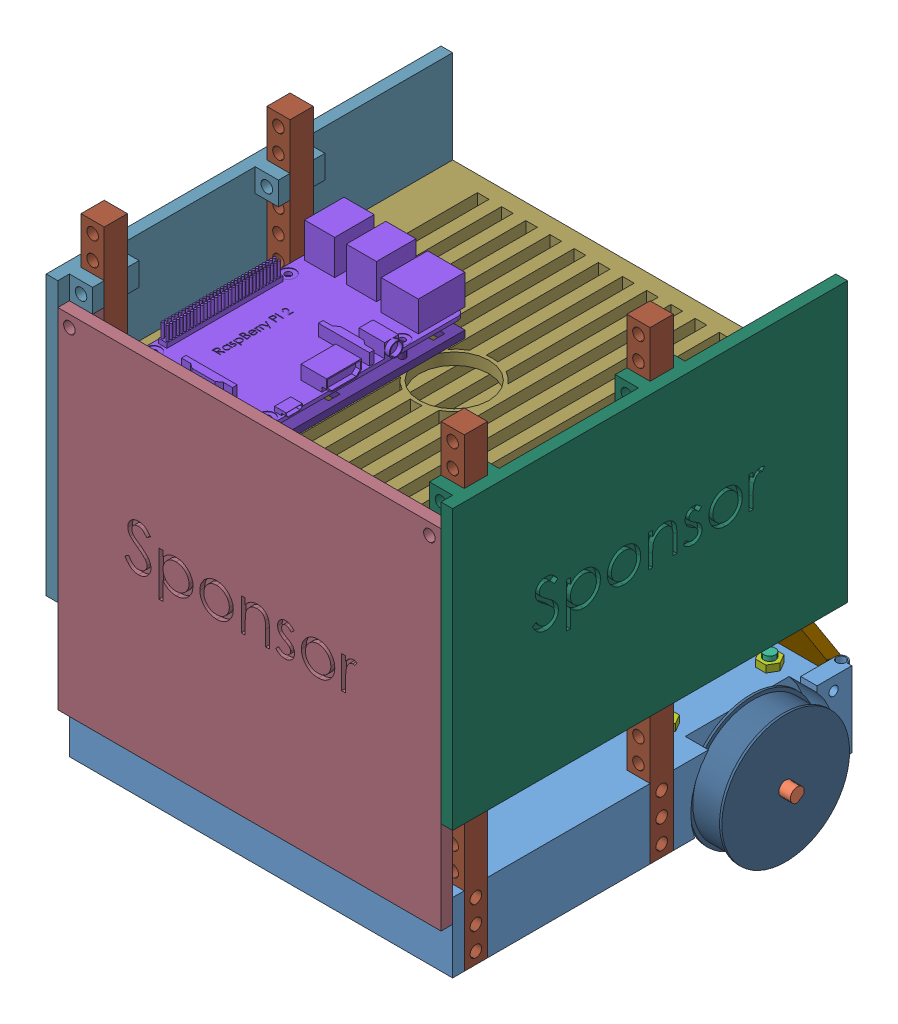
SolidWorks assembly base_robot2_assV4, configuration Défaut. Lengths in mm.
Overall size (196.8 228.59 210.36).
45 component instances, 19 part files, 95 mates.
Components (placement in the parent):
- base_robot2_modelV3-1: base_robot2_modelV3 [Défaut] at (-7.2062 -14.7881 165) size (169 32.5 172.25)
- moteur_IG320100-1: moteur_IG320100 [Défaut] at (-74.68 -4.7881 115) x (0 0.840643 0.541589) z (-1 0 0) size (32 32 94.7)
- moteur_IG320100-2: moteur_IG320100 [Défaut] at (60.2677 -4.7881 115) x (0 -0.613287 0.789861) z (1 0 0) size (32 32 94.7)
- patin_robot2_model-1: patin_robot2_model [Défaut] at (-59.7062 -24.7881 217.5) size (40 10 30)
- patin_robot2_model-2: patin_robot2_model [Défaut] at (45.2938 -24.7881 217.5) size (40 10 30)
- support_moteur_30mm-1: support_moteur_30mm [Défaut] at (11.7938 -4.7881 115) x (1 0 0) z (0 0 -1) size (10 9 52.36)
- support_moteur_30mm-2: support_moteur_30mm [Défaut] at (-26.2062 -4.7881 115) x (-1 0 0) z (0 0 1) size (10 9 52.36)
- support_moteur_32.02mm-1: support_moteur_32.02mm [Défaut] at (61.7938 -4.7881 115) x (-1 0 0) z (0 0 1) size (10 10.01 55.01)
- support_moteur_32.02mm-2: support_moteur_32.02mm [Défaut] at (-76.2062 -4.7881 115) x (1 0 0) z (0 0 -1) size (10 10.01 55.01)
- vis_5mm-1: vis_5mm [Défaut] at (16.7938 -19.7881 93.8197) x (0.187636 0 -0.982239) z (-0.982239 0 -0.187636) size (8 42.5 8)
- vis_5mm-2: vis_5mm [Défaut] at (56.7938 -19.7881 92.4972) x (-0.262741 0 -0.964866) z (-0.964866 0 0.262741) size (8 42.5 8)
- vis_5mm-3: vis_5mm [Défaut] at (16.7938 -19.7881 136.1803) x (0.587771 0 -0.809028) z (-0.809028 0 -0.587771) size (8 42.5 8)
- vis_5mm-4: vis_5mm [Défaut] at (56.7938 -19.7881 137.5028) x (-0.993067 0 0.117546) z (0.117546 0 0.993067) size (8 42.5 8)
- vis_5mm-5: vis_5mm [Défaut] at (-31.2062 -19.7881 136.1803) x (0.909957 0 -0.414702) z (-0.414702 0 -0.909957) size (8 42.5 8)
- vis_5mm-6: vis_5mm [Défaut] at (-71.2062 -19.7881 137.5028) x (0.689074 0 -0.724691) z (-0.724691 0 -0.689074) size (8 42.5 8)
- vis_5mm-7: vis_5mm [Défaut] at (-31.2062 -19.7881 93.8197) x (0.478965 0 -0.877834) z (-0.877834 0 -0.478965) size (8 42.5 8)
- vis_5mm-8: vis_5mm [Défaut] at (-71.2062 -19.7881 92.4972) x (0.586817 0 -0.80972) z (-0.80972 0 -0.586817) size (8 42.5 8)
- vis_5mm-9: vis_5mm [Défaut] at (45.2938 -19.7881 217.5) x (0.470882 0 0.882196) z (0.882196 0 -0.470882) size (8 42.5 8)
- vis_5mm-10: vis_5mm [Défaut] at (-59.7062 -19.7881 217.5) x (-0.905597 0 -0.424138) z (-0.424138 0 0.905597) size (8 42.5 8)
- ecrou_5mm_model-1: ecrou_5mm_model [Défaut] at (56.7938 15.2119 92.4972) size (9 3 7.79)
- raspberry-1: raspberry [Défaut] at (-48.6384 133.2119 188.8434) x (0 0 -1) z (1 0 0) size (89 17.6 58)
- arduino-1: arduino [Défaut] at (35.1773 70.2119 204.4796) x (0.009951 0 0.99995) z (-0.99995 0 0.009951) size (74.8 15.6 53.3)
- ecrou_5mm_model-2: ecrou_5mm_model [Défaut] at (-31.2062 15.2119 93.8197) size (9 3 7.79)
- ecrou_5mm_model-3: ecrou_5mm_model [Défaut] at (16.7938 15.2119 136.1803) size (9 3 7.79)
- ecrou_5mm_model-4: ecrou_5mm_model [Défaut] at (56.7938 15.2119 137.5028) size (9 3 7.79)
- ecrou_5mm_model-5: ecrou_5mm_model [Défaut] at (-31.2062 15.2119 136.1803) size (9 3 7.79)
- ecrou_5mm_model-6: ecrou_5mm_model [Défaut] at (16.7938 15.2119 93.8197) size (9 3 7.79)
- ecrou_5mm_model-7: ecrou_5mm_model [Défaut] at (-71.2062 15.2119 137.5028) size (9 3 7.79)
- ecrou_5mm_model-8: ecrou_5mm_model [Défaut] at (-71.2062 15.2119 92.4972) size (9 3 7.79)
- roue_imprimer_model-2: roue_imprimer_model [Défaut] at (-95.6062 -4.7881 115) x (1 0 0) z (0 0.840643 0.541589) size (15 55 55)
- roue_imprimer_model-3: roue_imprimer_model [Défaut] at (76.1938 -4.7881 115) x (1 0 0) z (0 0.613287 -0.789861) size (15 55 55)
- tige_robot2_model_V1-1: tige_robot2_model_V1 [Défaut] at (70.2938 85.2119 232.5) size (10 200 10)
- tige_robot2_model_V1-2: tige_robot2_model_V1 [Défaut] at (-84.7062 85.2119 232.5) size (10 200 10)
- tige_robot2_model_V1-3: tige_robot2_model_V1 [Défaut] at (70.2938 85.2119 152.5) size (10 200 10)
- tige_robot2_model_V1-4: tige_robot2_model_V1 [Défaut] at (-84.7062 85.2119 152.5) size (10 200 10)
- plaque_tige_robot2_V3_10mm-2: plaque_tige_robot2_V3_10mm [Défaut] at (-7.2062 115.2119 165) x (-1 0 0) z (0 0 -1) size (165 10 165)
- plaque_tige_robot2_V3_10mm-3: plaque_tige_robot2_V3_10mm [Défaut] at (-7.2062 55.2119 165) x (-1 0 0) z (0 0 -1) size (165 10 165)
- panneau_sponsor_robot2_150mm-1: panneau_sponsor_robot2_150mm [Défaut] at (-7.2062 80.2119 247.5) size (165 150 10)
- panneau_sponsor_robot2_gauche_120mm_model_V1-2: panneau_sponsor_robot2_gauche_120mm_model_V1 [Défaut] at (-89.7062 105.2119 167.5) x (0 0 1) z (-1 0 0) size (170 120 15)
- panneau_sponsor_robot2_droit_120mm_model_V1-2: panneau_sponsor_robot2_droit_120mm_model_V1 [Défaut] at (75.2938 105.2119 167.5) x (0 0 -1) z (1 0 0) size (170 120 15)
- fixation_support_plaque-1: fixation_support_plaque [Défaut] at (-78.2711 120.2119 120.1336) x (0 0 1) z (0 1 0) size (11 11 14)
- fixation_support_plaque-2: fixation_support_plaque [Défaut] at (-72.7344 128.2119 135.4302) x (1 0 0) z (0 -1 0) size (11 11 14)
- support_raspberry_plaque_robot2_modelV1-2: support_raspberry_plaque_robot2_modelV1 [Défaut] at (-48.6384 125.2119 188.7251) x (0 0 -1) z (1 0 0) size (85 8 56)
- plaque_chasse_neige_robot2_model_D-1: plaque_chasse_neige_robot2_model_D [Défaut] at (-2.5586 0.2119 50.8847) x (-0.941906 0 -0.335877) z (0 1 0) size (87.5 10 40)
- plaque_chasse_neige_robot2_model_G-1: plaque_chasse_neige_robot2_model_G [Défaut] at (-10.1444 0.2119 56.2728) x (0.963273 0 -0.268526) z (0 -1 0) size (87.5 10 40)
Mates (geometry in assembly coordinates):
- Coaxiale1: concentric aligned: cylinder of base_robot2_modelV3-1 through (-52.7062 -4.7881 115) axis (-1 0 0) radius 16.01; cylinder of moteur_IG320100-1 through (-95.28 -4.7881 115) axis (-1 0 0) radius 16
- Coïncidente1: coincident anti-aligned: plane of base_robot2_modelV3-1 through (-52.7062 -4.7881 115) normal (-1 0 0); plane of moteur_IG320100-1 through (-52.7062 -4.7881 115) normal (1 0 0)
- Coaxiale3: concentric aligned: cylinder of base_robot2_modelV3-1 through (38.2938 -4.7881 115) axis (1 0 0) radius 16.01; cylinder of moteur_IG320100-2 through (80.8677 -4.7881 115) axis (1 0 0) radius 16
- Coïncidente2: coincident anti-aligned: plane of base_robot2_modelV3-1 through (38.2938 -4.7881 115) normal (1 0 0); plane of moteur_IG320100-2 through (38.2938 -4.7881 115) normal (-1 0 0)
- Coaxiale4: concentric aligned: cylinder of base_robot2_modelV3-1 through (-59.7062 15.2119 217.5) axis (0 -1 0) radius 2.5; cylinder of patin_robot2_model-1 through (-59.7062 -14.7881 217.5) axis (0 -1 0) radius 2.5
- Coaxiale5: concentric aligned: cylinder of base_robot2_modelV3-1 through (45.2938 15.2119 217.5) axis (0 -1 0) radius 2.5; cylinder of patin_robot2_model-2 through (45.2938 -14.7881 217.5) axis (0 -1 0) radius 2.5
- Coïncidente3: coincident anti-aligned: plane of base_robot2_modelV3-1 through (-7.2062 -14.7881 165) normal (0 -1 0); plane of patin_robot2_model-1 through (-59.7062 -14.7881 217.5) normal (0 1 0)
- Coïncidente4: coincident anti-aligned: plane of base_robot2_modelV3-1 through (-7.2062 -14.7881 165) normal (0 -1 0); plane of patin_robot2_model-2 through (45.2938 -14.7881 217.5) normal (0 1 0)
- Coaxiale6: concentric anti-aligned: cylinder of base_robot2_modelV3-1 through (16.7938 15.2119 93.8197) axis (0 -1 0) radius 2.5; cylinder of support_moteur_30mm-1 through (16.7938 -23.7881 93.8197) axis (0 1 0) radius 2.5
- Coaxiale7: concentric anti-aligned: cylinder of moteur_IG320100-2 through (80.8677 -4.7881 115) axis (1 0 0) radius 15; cylinder of support_moteur_30mm-1 through (21.7938 -4.7881 115) axis (-1 0 0) radius 15
- Coaxiale8: concentric anti-aligned: cylinder of base_robot2_modelV3-1 through (-31.2062 15.2119 93.8197) axis (0 -1 0) radius 2.5; cylinder of support_moteur_30mm-2 through (-31.2062 -23.7881 93.8197) axis (0 1 0) radius 2.5
- Coaxiale9: concentric anti-aligned: cylinder of moteur_IG320100-1 through (-95.28 -4.7881 115) axis (-1 0 0) radius 15; cylinder of support_moteur_30mm-2 through (-36.2062 -4.7881 115) axis (1 0 0) radius 15
- Coaxiale10: concentric anti-aligned: cylinder of base_robot2_modelV3-1 through (56.7938 15.2119 92.4972) axis (0 -1 0) radius 2.5; cylinder of support_moteur_32.02mm-1 through (56.7938 -24.7981 92.4972) axis (0 1 0) radius 2.5
- Coaxiale12: concentric aligned: cylinder of moteur_IG320100-2 through (80.8677 -4.7881 115) axis (1 0 0) radius 16; cylinder of support_moteur_32.02mm-1 through (51.7938 -4.7881 115) axis (1 0 0) radius 16.01
- Coaxiale13: concentric aligned: cylinder of moteur_IG320100-1 through (-95.28 -4.7881 115) axis (-1 0 0) radius 16; cylinder of support_moteur_32.02mm-2 through (-66.2062 -4.7881 115) axis (-1 0 0) radius 16.01
- Coaxiale14: concentric anti-aligned: cylinder of base_robot2_modelV3-1 through (-71.2062 15.2119 137.5028) axis (0 -1 0) radius 2.5; cylinder of support_moteur_32.02mm-2 through (-71.2062 -24.7981 137.5028) axis (0 1 0) radius 2.5
- Coaxiale16: concentric aligned: cylinder of base_robot2_modelV3-1 through (16.7938 15.2119 93.8197) axis (0 -1 0) radius 2.5; cylinder of vis_5mm-1 through (16.7938 20.2119 93.8197) axis (0 -1 0) radius 2.5
- Coïncidente6: coincident anti-aligned: plane of support_moteur_30mm-1 through (21.7938 -19.7881 115) normal (0 -1 0); plane of vis_5mm-1 through (16.7938 -19.7881 93.8197) normal (0 1 0)
- Coaxiale17: concentric aligned: cylinder of base_robot2_modelV3-1 through (56.7938 15.2119 92.4972) axis (0 -1 0) radius 2.5; cylinder of vis_5mm-2 through (56.7938 20.2119 92.4972) axis (0 -1 0) radius 2.5
- Coïncidente7: coincident anti-aligned: plane of support_moteur_32.02mm-1 through (51.7938 -19.7881 87.4972) normal (0 -1 0); plane of vis_5mm-2 through (56.7938 -19.7881 92.4972) normal (0 1 0)
- Coaxiale18: concentric anti-aligned: cylinder of support_moteur_32.02mm-1 through (56.7938 -24.7981 137.5028) axis (0 1 0) radius 2.5; cylinder of vis_5mm-4 through (56.7938 20.2119 137.5028) axis (0 -1 0) radius 2.5
- Coïncidente8: coincident anti-aligned: plane of support_moteur_32.02mm-1 through (51.7938 -19.7881 142.5028) normal (0 -1 0); plane of vis_5mm-4 through (56.7938 -19.7881 137.5028) normal (0 1 0)
- Coaxiale20: concentric anti-aligned: cylinder of support_moteur_30mm-1 through (16.7938 -23.7881 136.1803) axis (0 1 0) radius 2.5; cylinder of vis_5mm-3 through (16.7938 20.2119 136.1803) axis (0 -1 0) radius 2.5
- Coïncidente9: coincident anti-aligned: plane of support_moteur_30mm-1 through (21.7938 -19.7881 115) normal (0 -1 0); plane of vis_5mm-3 through (16.7938 -19.7881 136.1803) normal (0 1 0)
- Coaxiale21: concentric anti-aligned: cylinder of support_moteur_30mm-2 through (-31.2062 -23.7881 93.8197) axis (0 1 0) radius 2.5; cylinder of vis_5mm-7 through (-31.2062 20.2119 93.8197) axis (0 -1 0) radius 2.5
- Coaxiale22: concentric anti-aligned: cylinder of support_moteur_32.02mm-2 through (-71.2062 -24.7981 92.4972) axis (0 1 0) radius 2.5; cylinder of vis_5mm-8 through (-71.2062 20.2119 92.4972) axis (0 -1 0) radius 2.5
- Coaxiale23: concentric anti-aligned: cylinder of support_moteur_32.02mm-2 through (-71.2062 -24.7981 137.5028) axis (0 1 0) radius 2.5; cylinder of vis_5mm-6 through (-71.2062 20.2119 137.5028) axis (0 -1 0) radius 2.5
- Coaxiale24: concentric anti-aligned: cylinder of support_moteur_30mm-2 through (-31.2062 -23.7881 136.1803) axis (0 1 0) radius 2.5; cylinder of vis_5mm-5 through (-31.2062 20.2119 136.1803) axis (0 -1 0) radius 2.5
- Coïncidente10: coincident anti-aligned: plane of support_moteur_30mm-2 through (-36.2062 -19.7881 115) normal (0 -1 0); plane of vis_5mm-5 through (-31.2062 -19.7881 136.1803) normal (0 1 0)
- Coïncidente11: coincident anti-aligned: plane of support_moteur_32.02mm-2 through (-66.2062 -19.7881 142.5028) normal (0 -1 0); plane of vis_5mm-6 through (-71.2062 -19.7881 137.5028) normal (0 1 0)
- Coïncidente12: coincident anti-aligned: plane of support_moteur_32.02mm-2 through (-66.2062 -19.7881 87.4972) normal (0 -1 0); plane of vis_5mm-8 through (-71.2062 -19.7881 92.4972) normal (0 1 0)
- Coïncidente13: coincident anti-aligned: plane of support_moteur_30mm-2 through (-36.2062 -19.7881 115) normal (0 -1 0); plane of vis_5mm-7 through (-31.2062 -19.7881 93.8197) normal (0 1 0)
- Coaxiale25: concentric aligned: cylinder of base_robot2_modelV3-1 through (45.2938 15.2119 217.5) axis (0 -1 0) radius 2.5; cylinder of vis_5mm-9 through (45.2938 20.2119 217.5) axis (0 -1 0) radius 2.5
- Coïncidente14: coincident anti-aligned: plane of patin_robot2_model-2 through (45.2938 -19.7881 217.5) normal (0 -1 0); plane of vis_5mm-9 through (45.2938 -19.7881 217.5) normal (0 1 0)
- Coaxiale26: concentric aligned: cylinder of base_robot2_modelV3-1 through (-59.7062 15.2119 217.5) axis (0 -1 0) radius 2.5; cylinder of vis_5mm-10 through (-59.7062 20.2119 217.5) axis (0 -1 0) radius 2.5
- Coïncidente15: coincident anti-aligned: plane of patin_robot2_model-1 through (-59.7062 -19.7881 217.5) normal (0 -1 0); plane of vis_5mm-10 through (-59.7062 -19.7881 217.5) normal (0 1 0)
- Coaxiale27: concentric aligned: cylinder of vis_5mm-2 through (56.7938 20.2119 92.4972) axis (0 -1 0) radius 2.5; cylinder of ecrou_5mm_model-1 through (56.7938 18.2119 92.4972) axis (0 -1 0) radius 2.5
- Coïncidente16: coincident anti-aligned: plane of base_robot2_modelV3-1 through (-7.2062 15.2119 165) normal (0 1 0); plane of ecrou_5mm_model-1 through (56.7938 15.2119 92.4972) normal (0 -1 0)
- Coaxiale30: concentric aligned: cylinder of vis_5mm-4 through (56.7938 20.2119 137.5028) axis (0 -1 0) radius 2.5; cylinder of ecrou_5mm_model-4 through (56.7938 18.2119 137.5028) axis (0 -1 0) radius 2.5
- Coaxiale31: concentric aligned: cylinder of vis_5mm-3 through (16.7938 20.2119 136.1803) axis (0 -1 0) radius 2.5; cylinder of ecrou_5mm_model-3 through (16.7938 18.2119 136.1803) axis (0 -1 0) radius 2.5
- Coaxiale32: concentric aligned: cylinder of vis_5mm-1 through (16.7938 20.2119 93.8197) axis (0 -1 0) radius 2.5; cylinder of ecrou_5mm_model-6 through (16.7938 18.2119 93.8197) axis (0 -1 0) radius 2.5
- Coaxiale33: concentric aligned: cylinder of vis_5mm-8 through (-71.2062 20.2119 92.4972) axis (0 -1 0) radius 2.5; cylinder of ecrou_5mm_model-8 through (-71.2062 18.2119 92.4972) axis (0 -1 0) radius 2.5
- Coïncidente19: coincident anti-aligned: cylinder of vis_5mm-6 through (-71.2062 20.2119 137.5028) axis (0 -1 0) radius 2.5; circle of ecrou_5mm_model-7
- Coaxiale34: concentric aligned: cylinder of vis_5mm-5 through (-31.2062 20.2119 136.1803) axis (0 -1 0) radius 2.5; cylinder of ecrou_5mm_model-5 through (-31.2062 18.2119 136.1803) axis (0 -1 0) radius 2.5
- Coaxiale35: concentric aligned: cylinder of vis_5mm-7 through (-31.2062 20.2119 93.8197) axis (0 -1 0) radius 2.5; cylinder of ecrou_5mm_model-2 through (-31.2062 18.2119 93.8197) axis (0 -1 0) radius 2.5
- Coïncidente20: coincident anti-aligned: plane of base_robot2_modelV3-1 through (-7.2062 15.2119 165) normal (0 1 0); plane of ecrou_5mm_model-4 through (56.7938 15.2119 137.5028) normal (0 -1 0)
- Coïncidente21: coincident anti-aligned: plane of base_robot2_modelV3-1 through (-7.2062 15.2119 165) normal (0 1 0); plane of ecrou_5mm_model-6 through (16.7938 15.2119 93.8197) normal (0 -1 0)
- Coïncidente22: coincident anti-aligned: plane of base_robot2_modelV3-1 through (-7.2062 15.2119 165) normal (0 1 0); plane of ecrou_5mm_model-3 through (16.7938 15.2119 136.1803) normal (0 -1 0)
- Coïncidente23: coincident anti-aligned: plane of base_robot2_modelV3-1 through (-7.2062 15.2119 165) normal (0 1 0); plane of ecrou_5mm_model-5 through (-31.2062 15.2119 136.1803) normal (0 -1 0)
- Coïncidente24: coincident anti-aligned: plane of base_robot2_modelV3-1 through (-7.2062 15.2119 165) normal (0 1 0); plane of ecrou_5mm_model-8 through (-71.2062 15.2119 92.4972) normal (0 -1 0)
- Coïncidente25: coincident anti-aligned: plane of base_robot2_modelV3-1 through (-7.2062 15.2119 165) normal (0 1 0); plane of ecrou_5mm_model-2 through (-31.2062 15.2119 93.8197) normal (0 -1 0)
- Coïncidente26: coincident anti-aligned: plane of base_robot2_modelV3-1 through (-7.2062 15.2119 165) normal (0 1 0); plane of ecrou_5mm_model-7 through (-71.2062 15.2119 137.5028) normal (0 -1 0)
- Coaxiale36: concentric anti-aligned: cylinder of moteur_IG320100-1 through (-95.28 -4.7881 115) axis (-1 0 0) radius 3; cylinder of roue_imprimer_model-2 through (-100.6062 -4.7881 115) axis (1 0 0) radius 3
- Coïncidente27: coincident anti-aligned: plane of moteur_IG320100-1 through (-93.6062 -4.8281 112.0003) normal (0 0.541589 -0.840643); plane of roue_imprimer_model-2 through (-100.6062 -2.04 113.7965) normal (0 -0.541589 0.840643)
- Distance1: distance = 5 mm aligned: plane of moteur_IG320100-1 through (-105.6062 -4.7881 115) normal (-1 0 0); plane of roue_imprimer_model-2 through (-100.6062 -4.7881 115) normal (-1 0 0)
- Coïncidente29: coincident anti-aligned: plane of moteur_IG320100-2 through (79.1938 -5.7457 112.1569) normal (0 -0.789861 -0.613287); plane of roue_imprimer_model-3 through (71.1938 -5.7457 112.1569) normal (0 0.789861 0.613287)
- Coaxiale37: concentric aligned: cylinder of moteur_IG320100-2 through (80.8677 -4.7881 115) axis (1 0 0) radius 3; cylinder of roue_imprimer_model-3 through (71.1938 -4.7881 115) axis (1 0 0) radius 3
- Distance2: distance = 5 mm aligned: plane of roue_imprimer_model-3 through (86.1938 -4.7881 115) normal (1 0 0); plane of moteur_IG320100-2 through (91.1938 -4.7881 115) normal (1 0 0)
- Coaxiale40: concentric anti-aligned: cylinder of base_robot2_modelV3-1 through (-91.7072 10.2119 237.5) axis (1 0 0) radius 2.5; cylinder of tige_robot2_model_V1-1 through (75.2938 10.2119 237.5) axis (-1 0 0) radius 2.5
- Coaxiale41: concentric anti-aligned: cylinder of base_robot2_modelV3-1 through (-91.7072 -9.7881 237.5) axis (1 0 0) radius 2.5; cylinder of tige_robot2_model_V1-1 through (75.2938 -9.7881 237.5) axis (-1 0 0) radius 2.5
- Coïncidente32: coincident anti-aligned: plane of base_robot2_modelV3-1 through (65.2938 -14.7881 165) normal (1 0 0); plane of tige_robot2_model_V1-1 through (65.2938 185.2119 242.5) normal (-1 0 0)
- Coaxiale42: concentric anti-aligned: cylinder of base_robot2_modelV3-1 through (-91.7072 10.2119 157.5) axis (1 0 0) radius 2.5; cylinder of tige_robot2_model_V1-3 through (75.2938 10.2119 157.5) axis (-1 0 0) radius 2.5
- Coaxiale43: concentric anti-aligned: cylinder of base_robot2_modelV3-1 through (-91.7072 -9.7881 157.5) axis (1 0 0) radius 2.5; cylinder of tige_robot2_model_V1-3 through (75.2938 -9.7881 157.5) axis (-1 0 0) radius 2.5
- Coïncidente33: coincident anti-aligned: plane of base_robot2_modelV3-1 through (65.2938 -14.7881 165) normal (1 0 0); plane of tige_robot2_model_V1-3 through (65.2938 185.2119 162.5) normal (-1 0 0)
- Coaxiale44: concentric anti-aligned: cylinder of base_robot2_modelV3-1 through (-91.7072 10.2119 237.5) axis (1 0 0) radius 2.5; cylinder of tige_robot2_model_V1-2 through (-79.7062 10.2119 237.5) axis (-1 0 0) radius 2.5
- Coaxiale45: concentric anti-aligned: cylinder of base_robot2_modelV3-1 through (-91.7072 -9.7881 237.5) axis (1 0 0) radius 2.5; cylinder of tige_robot2_model_V1-2 through (-79.7062 -9.7881 237.5) axis (-1 0 0) radius 2.5
- Coïncidente34: coincident anti-aligned: plane of base_robot2_modelV3-1 through (-79.7062 -14.7881 165) normal (-1 0 0); plane of tige_robot2_model_V1-2 through (-79.7062 185.2119 242.5) normal (1 0 0)
- Coaxiale46: concentric anti-aligned: cylinder of base_robot2_modelV3-1 through (-91.7072 10.2119 157.5) axis (1 0 0) radius 2.5; cylinder of tige_robot2_model_V1-4 through (-79.7062 10.2119 157.5) axis (-1 0 0) radius 2.5
- Coaxiale47: concentric anti-aligned: cylinder of base_robot2_modelV3-1 through (-91.7072 -9.7881 157.5) axis (1 0 0) radius 2.5; cylinder of tige_robot2_model_V1-4 through (-79.7062 -9.7881 157.5) axis (-1 0 0) radius 2.5
- Coïncidente35: coincident anti-aligned: plane of base_robot2_modelV3-1 through (-79.7062 -14.7881 165) normal (-1 0 0); plane of tige_robot2_model_V1-4 through (-79.7062 185.2119 162.5) normal (1 0 0)
- Coaxiale48: concentric anti-aligned: cylinder of tige_robot2_model_V1-3 through (70.2938 60.2119 162.5) axis (0 0 -1) radius 2.5; cylinder of plaque_tige_robot2_V3_10mm-3 through (70.2938 60.2119 82.5) axis (0 0 1) radius 2.5
- Coaxiale49: concentric anti-aligned: cylinder of tige_robot2_model_V1-2 through (-84.7062 60.2119 242.5) axis (0 0 -1) radius 2.5; cylinder of plaque_tige_robot2_V3_10mm-3 through (-84.7062 60.2119 82.5) axis (0 0 1) radius 2.5
- Coïncidente37: coincident anti-aligned: plane of tige_robot2_model_V1-2 through (-84.7062 85.2119 242.5) normal (0 0 1); plane of plaque_tige_robot2_V3_10mm-3 through (-7.2062 65.2119 242.5) normal (0 0 -1)
- Coïncidente38: coincident anti-aligned: plane of tige_robot2_model_V1-2 through (-84.7062 85.2119 242.5) normal (0 0 1); plane of plaque_tige_robot2_V3_10mm-2 through (-7.2062 125.2119 242.5) normal (0 0 -1)
- Distance3: distance = 5 mm anti-aligned: plane of arduino-1 through (35.1773 70.2119 204.4796) normal (0 -1 0); plane of plaque_tige_robot2_V3_10mm-3 through (-7.2062 65.2119 165) normal (0 1 0)
- Coaxiale51: concentric aligned: cylinder of tige_robot2_model_V1-2 through (-84.7062 150.2119 242.5) axis (0 0 -1) radius 2.5; cylinder of panneau_sponsor_robot2_150mm-1 through (-84.7062 150.2119 252.5) axis (0 0 -1) radius 2.5
- Coïncidente39: coincident anti-aligned: plane of tige_robot2_model_V1-2 through (-84.7062 85.2119 242.5) normal (0 0 1); plane of panneau_sponsor_robot2_150mm-1 through (-89.7062 145.2119 242.5) normal (0 0 -1)
- Coïncidente40: coincident anti-aligned: plane of plaque_tige_robot2_V3_10mm-2 through (-89.7062 125.2119 165) normal (-1 0 0); plane of panneau_sponsor_robot2_gauche_120mm_model_V1-2 through (-89.7062 105.2119 167.5) normal (1 0 0)
- Coïncidente41: coincident anti-aligned: plane of tige_robot2_model_V1-2 through (-84.7062 85.2119 232.5) normal (0 0 -1); plane of panneau_sponsor_robot2_gauche_120mm_model_V1-2 through (-89.7062 155.2119 232.5) normal (0 0 1)
- Coaxiale54: concentric anti-aligned: cylinder of tige_robot2_model_V1-2 through (-84.7062 160.2119 242.5) axis (0 0 -1) radius 2.5; cylinder of panneau_sponsor_robot2_gauche_120mm_model_V1-2 through (-84.7062 160.2119 82.5) axis (0 0 1) radius 2.5
- Coaxiale55: concentric anti-aligned: cylinder of tige_robot2_model_V1-4 through (-84.7062 160.2119 162.5) axis (0 0 -1) radius 2.5; cylinder of panneau_sponsor_robot2_gauche_120mm_model_V1-2 through (-84.7062 160.2119 82.5) axis (0 0 1) radius 2.5
- Coaxiale56: concentric aligned: cylinder of tige_robot2_model_V1-1 through (70.2938 160.2119 242.5) axis (0 0 -1) radius 2.5; cylinder of panneau_sponsor_robot2_droit_120mm_model_V1-2 through (70.2938 160.2119 252.5) axis (0 0 -1) radius 2.5
- Coïncidente42: coincident anti-aligned: plane of tige_robot2_model_V1-1 through (70.2938 85.2119 242.5) normal (0 0 1); plane of panneau_sponsor_robot2_droit_120mm_model_V1-2 through (75.2938 155.2119 242.5) normal (0 0 -1)
- Coïncidente43: coincident anti-aligned: plane of tige_robot2_model_V1-3 through (75.2938 185.2119 162.5) normal (1 0 0); plane of panneau_sponsor_robot2_droit_120mm_model_V1-2 through (75.2938 105.2119 167.5) normal (-1 0 0)
- Coaxiale57: concentric anti-aligned: cylinder of tige_robot2_model_V1-1 through (70.2938 120.2119 242.5) axis (0 0 -1) radius 2.5; circle of tige_robot2_model_V1-3
- Coaxiale58: concentric anti-aligned: cylinder of tige_robot2_model_V1-4 through (-84.7062 120.2119 162.5) axis (0 0 -1) radius 2.5; cylinder of plaque_tige_robot2_V3_10mm-2 through (-84.7062 120.2119 82.5) axis (0 0 1) radius 2.5
- Coïncidente49: coincident: plane of plaque_tige_robot2_V3_10mm-2 through (-40.9562 125.2119 165) normal (1 0 0); line of fixation_support_plaque-2 through (-40.9562 128.7119 153.9118) axis (0 -1 0)
- Coïncidente52: coincident anti-aligned: plane of plaque_tige_robot2_V3_10mm-2 through (-56.7895 125.2119 165) normal (-1 0 0); plane of fixation_support_plaque-1 through (-56.7895 128.2119 151.9118) normal (1 0 0)
- Coïncidente53: coincident anti-aligned: plane of plaque_tige_robot2_V3_10mm-2 through (-7.2062 125.2119 165) normal (0 1 0); plane of support_raspberry_plaque_robot2_modelV1-2 through (-48.6384 125.2119 188.7251) normal (0 -1 0)
- Coaxiale59: concentric aligned: cylinder of raspberry-1 through (-24.1384 134.8119 227.8434) axis (0 -1 0) radius 1.375; cylinder of support_raspberry_plaque_robot2_modelV1-2 through (-24.1384 133.2119 227.8434) axis (0 -1 0) radius 1.375
- Coïncidente55: coincident anti-aligned: plane of fixation_support_plaque-2 through (-40.9562 120.2119 151.9118) normal (0 0 -1); plane of support_raspberry_plaque_robot2_modelV1-2 through (-73.6384 128.2119 151.9118) normal (0 0 1)
- Coaxiale60: concentric aligned: cylinder of base_robot2_modelV3-1 through (-87.2062 -4.7881 77.7549) axis (0 -1 0) radius 2; cylinder of plaque_chasse_neige_robot2_model_G-1 through (-87.2062 5.2119 77.7549) axis (0 -1 0) radius 2
- Coïncidente56: coincident anti-aligned: plane of base_robot2_modelV3-1 through (-7.2062 -4.7881 165) normal (0 1 0); plane of plaque_chasse_neige_robot2_model_G-1 through (-87.2062 -4.7881 77.7549) normal (0 -1 0)
- Coaxiale62: concentric aligned: cylinder of base_robot2_modelV3-1 through (72.7938 5.2119 77.7549) axis (0 1 0) radius 2; cylinder of plaque_chasse_neige_robot2_model_D-1 through (72.7938 -4.7881 77.7549) axis (0 1 0) radius 2
- Coïncidente57: coincident anti-aligned: plane of base_robot2_modelV3-1 through (-7.2062 -4.7881 165) normal (0 1 0); plane of plaque_chasse_neige_robot2_model_D-1 through (72.7938 -4.7881 77.7549) normal (0 -1 0)
